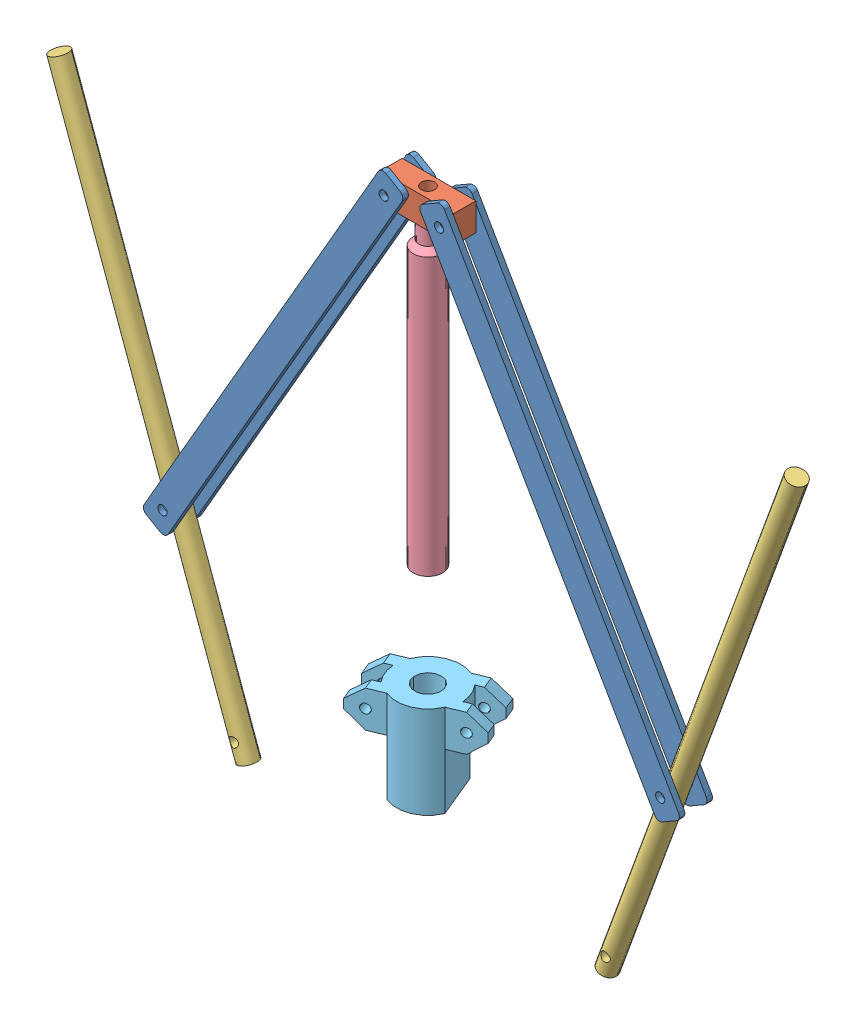
SolidWorks assembly ЗаклепочникСб, configuration По умолчанию. Lengths in mm.
Overall size (409.36 325.33 55.23).
9 component instances, 5 part files, 23 mates.
Components (placement in the parent):
- Тяга-1: Тяга [По умолчанию] at (-75 -96.423 6) x (0 0 1) z (-0.5 -0.866025 0) size (3 15 260)
- Упор-1: Упор [По умолчанию] at origin size (40 15 12)
- Тяга-2: Тяга [По умолчанию] at (-75 -96.423 -9) x (0 0 1) z (-0.5 -0.866025 0) size (3 15 260)
- Тяга-3: Тяга [По умолчанию] at (75 -96.423 6) x (0 0 1) z (0.5 -0.866025 0) size (3 15 260)
- Тяга-4: Тяга [По умолчанию] at (75 -96.423 -9) x (0 0 1) z (0.5 -0.866025 0) size (3 15 260)
- Рукоятка-1: Рукоятка [По умолчанию] at (-97.3778 -303.7123 0.0308) x (0 0 1) z (-0.939693 -0.34202 0) size (10 300 10)
- Рукоятка-2: Рукоятка [По умолчанию] at (97.3778 -303.7123 -0.0945) x (0 0 1) z (-0.939693 0.34202 0) size (10 300 10)
- Штанга-1: Штанга [По умолчанию] at (0 -162.8371 0) size (16 162.84 16)
- Корпус-1: Корпус [По умолчанию] at (0 -268.7671 0) x (0.924228 0 -0.381841) z (0.381841 0 0.924228) size (60 50 34.97)
Mates (geometry in assembly coordinates):
- Параллельность2: parallel: plane of Упор-1 through (-20 15 6) normal (0 0 1); plane of assembly through (0 0 0) normal (0 0 1)
- Совпадение3: coincident: plane of Упор-1 through (0 0 0) normal (0 -1 0); plane of assembly through (0 0 0) normal (0 1 0)
- Параллельность3: parallel: plane of Упор-1 through (-20 15 6) normal (-1 0 0); plane of assembly through (0 0 0) normal (1 0 0)
- Совпадение8: coordinate: point of Упор-1; point of assembly
- Концентричный1: concentric anti-aligned: cylinder of Тяга-1 through (-15 7.5 9) axis (0 0 -1) radius 2.5; cylinder of Упор-1 through (-15 7.5 -6) axis (0 0 1) radius 2.5
- Совпадение9: coincident anti-aligned: plane of Тяга-1 through (-134.6029 -208.6583 6) normal (0 0 -1); plane of Упор-1 through (-20 15 6) normal (0 0 1)
- Концентричный2: concentric anti-aligned: cylinder of Упор-1 through (-15 7.5 -6) axis (0 0 1) radius 2.5; cylinder of Тяга-2 through (-15 7.5 -6) axis (0 0 -1) radius 2.5
- Совпадение10: coincident anti-aligned: plane of Упор-1 through (-20 15 -6) normal (0 0 -1); plane of Тяга-2 through (-134.6029 -208.6583 -6) normal (0 0 1)
- Совпадение11: coincident aligned: plane of Тяга-1 through (-144.9952 -202.6583 9) normal (-0.866025 0.5 0); plane of Тяга-2 through (-144.9952 -202.6583 -6) normal (-0.866025 0.5 0)
- Угол1: planar angle = 1.047198 rad aligned: plane of Тяга-1 through (-144.9952 -202.6583 9) normal (-0.866025 0.5 0); plane of Упор-1 through (0 15 0) normal (0 1 0)
- Концентричный3: concentric anti-aligned: cylinder of Упор-1 through (15 7.5 -6) axis (0 0 1) radius 2.5; cylinder of Тяга-3 through (15 7.5 9) axis (0 0 -1) radius 2.5
- Совпадение13: coincident anti-aligned: plane of Упор-1 through (-20 15 6) normal (0 0 1); plane of Тяга-3 through (142.3971 -204.1583 6) normal (0 0 -1)
- Угол2: planar angle = 2.094395 rad anti-aligned: plane of Тяга-3 through (144.9952 -202.6583 9) normal (0.866025 0.5 0); plane of Упор-1 through (0 15 0) normal (0 1 0)
- Концентричный4: concentric anti-aligned: cylinder of Упор-1 through (15 7.5 -6) axis (0 0 1) radius 2.5; cylinder of Тяга-4 through (15 7.5 -6) axis (0 0 -1) radius 2.5
- Совпадение15: coincident anti-aligned: plane of Упор-1 through (-20 15 -6) normal (0 0 -1); plane of Тяга-4 through (142.3971 -204.1583 -6) normal (0 0 1)
- Совпадение16: coincident aligned: plane of Тяга-3 through (144.9952 -202.6583 9) normal (0.866025 0.5 0); plane of Тяга-4 through (144.9952 -202.6583 -6) normal (0.866025 0.5 0)
- Концентричный5: concentric anti-aligned: cylinder of Тяга-1 through (-135 -200.3461 9) axis (0 0 -1) radius 2.5; cylinder of Рукоятка-1 through (-135 -200.3461 -4.9692) axis (0 0 1) radius 2.5
- Концентричный6: concentric anti-aligned: cylinder of Тяга-3 through (135 -200.3461 9) axis (0 0 -1) radius 2.5; cylinder of Рукоятка-2 through (135 -200.3461 -5.0945) axis (0 0 1) radius 2.5
- Угол3: planar angle = 0.349066 rad aligned: plane of Рукоятка-2 through (97.3778 -303.7123 -0.0945) normal (-0.34202 -0.939693 0); plane of Упор-1 through (0 0 0) normal (0 -1 0)
- Угол4: planar angle = 0.349066 rad aligned: plane of Рукоятка-1 through (-97.3778 -303.7123 0.0308) normal (0.34202 -0.939693 0); plane of Упор-1 through (0 0 0) normal (0 -1 0)
- Концентричный7: concentric aligned: cylinder of Упор-1 through (0 15 0) axis (0 -1 0) radius 3.6; cylinder of Штанга-1 through (0 -182.1919 0) axis (0 -1 0) radius 2
- Расстояние1: distance = 15 mm aligned: plane of Штанга-1 through (0 0 -2) normal (0 1 0); plane of Упор-1 through (0 15 0) normal (0 1 0)
- Концентричный8: concentric aligned: cylinder of Штанга-1 through (0 -182.1919 0) axis (0 -1 0) radius 8; cylinder of Корпус-1 through (0 -218.7671 0) axis (0 -1 0) radius 7.1798
